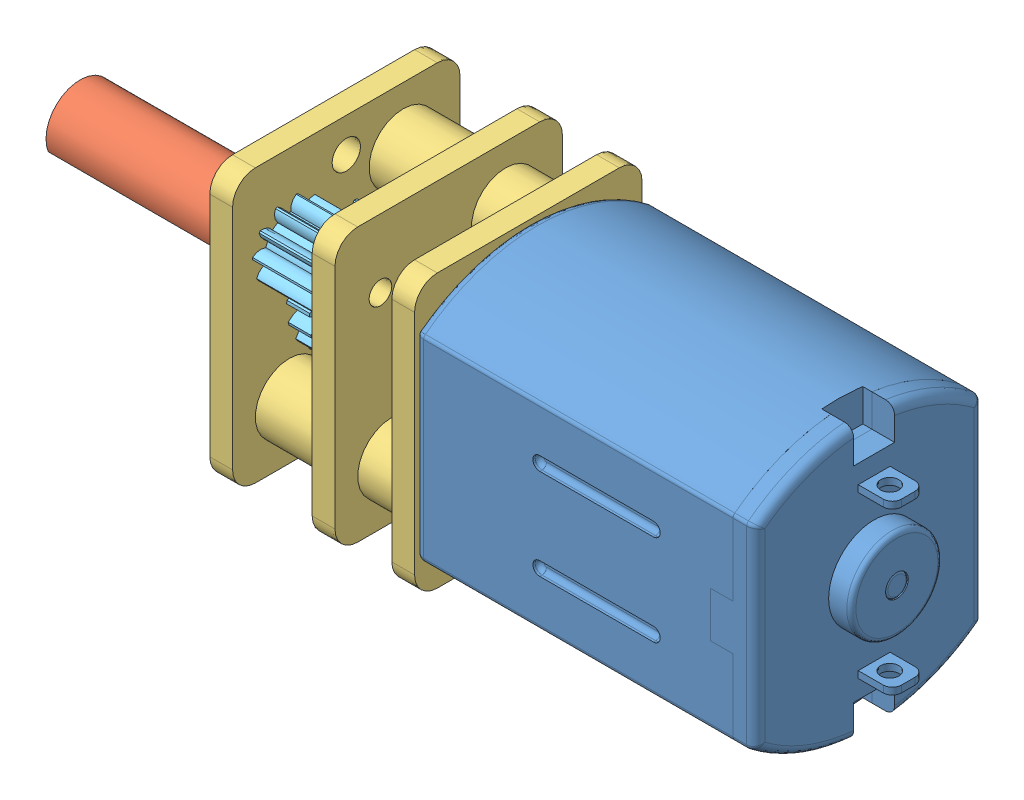
SolidWorks assembly n20 motor, configuration 轴长10mm. Lengths in mm.
Overall size (36.2 12.14 10.87).
11 component instances, 5 part files, 21 mates.
Components (placement in the parent):
- motor-1: motor [默认] at (-3.4114 0.0905 -5.0483)
- n20_shaft-1: n20_shaft [10mm] at (-13.1114 0.0905 -0.0483) x (0 -0.354131 -0.935196) z (0 0.935196 -0.354131) size (3 12 3)
- n20_gearbox-1: n20_gearbox [默认] at (-11.4114 0.0905 -0.0483) x (0 1 0) z (-1 0 0)
- cross recessed countersunk head screws gb1-1: cross recessed countersunk head screws gb1 [GB_CROSS_SCREWS_TYPE4 M1.6X3-2  H type-N] at (-12.4614 -3.4095 2.4517)
- cross recessed countersunk head screws gb1-2: cross recessed countersunk head screws gb1 [GB_CROSS_SCREWS_TYPE4 M1.6X3-2  H type-N] at (-12.4614 3.5905 -2.5483) x (1 0 0) z (0 0.116872 0.993147)
- spur gear_gb-1: spur gear_gb [GB - Spur gear 0.25M 10T 20PA 2FW ---S10A75H50L1.0N] at (-8.4114 -2.9095 -2.5483) x (1 0 0) z (0 -0.845955 0.533254)
- spur gear_gb-2: spur gear_gb [GB - Spur gear 0.25M 10T 20PA 2FW ---S10A75H50L1.0N] at (-4.4114 0.0905 -0.0483) x (-1 0 0) z (0 0.404067 -0.914729)
- spur gear_gb-4: spur gear_gb [GB - Spur gear 0.25M 16T 20PA 2FW ---S16A75H50L1.0N] at (-6.4114 -2.9095 -2.5483) x (1 0 0) z (0 -0.712706 0.701463)
- spur gear_gb-6: spur gear_gb [GB - Spur gear 0.25M 19T 20PA 2FW ---S19A75H50L1.0N] at (-9.9114 0.0905 -0.0483) x (1 0 0) z (0 0.321468 -0.94692)
- spur gear_gb-8: spur gear_gb [GB - Spur gear 0.25M 11T 20PA 3FW ---S11A75H50L1.0N] at (-10.9114 3.0905 2.9517) x (1 0 0) z (0 -0.604063 0.796937)
- spur gear_gb-10: spur gear_gb [GB - Spur gear 0.25M 19T 20PA 1FW ---S19A75H50L1.0N] at (-11.4114 0.0905 -0.0483) x (1 0 0) z (0 -0.330889 0.94367)
Mates (geometry in assembly coordinates):
- 同心1: concentric: cylinder of motor-1 through (-6.4114 0.0905 -0.0483) axis (1 0 0) radius 1; cylinder of n20_gearbox-1 through (-3.4114 0.0905 -0.0483) axis (-1 0 0) radius 0.5329
- 重合1: coincident: plane of motor-1 through (-3.4114 -5.9095 4.9517) normal (-1 0 0); plane of n20_gearbox-1 through (-3.4114 0.0905 -0.0483) normal (1 0 0)
- 重合2: coincident: plane of motor-1 through (-3.4114 0.0905 4.9517) normal (0 0 1); plane of n20_gearbox-1 through (-3.4114 6.0905 4.9517) normal (0 0 1)
- 同心2: concentric: cylinder of n20_shaft-1 through (-23.1114 0.0905 -0.0483) axis (1 0 0) radius 1.5; cylinder of n20_gearbox-1 through (-12.4114 0.0905 -0.0483) axis (1 0 0) radius 1.5
- 同心3: concentric: cylinder of n20_gearbox-1 through (-7.9114 3.5905 -2.5483) axis (-1 0 0) radius 0.9; cone of cross recessed countersunk head screws gb1-2 through (-11.4614 3.5905 -2.5483) axis (1 0 0)
- 重合4: coincident: cone of n20_gearbox-1 through (-12.4114 3.5905 -2.5483) axis (1 0 0); cone of cross recessed countersunk head screws gb1-2 through (-11.4614 3.5905 -2.5483) axis (1 0 0)
- 同心8: concentric: cylinder of n20_gearbox-1 through (-7.9114 -3.4095 2.4517) axis (-1 0 0) radius 0.9; cylinder of cross recessed countersunk head screws gb1-1 through (-7.9456 -3.4095 2.4517) axis (1 0 0) radius 0.8
- 重合5: coincident: cone of n20_gearbox-1 through (-12.4114 -3.4095 2.4517) axis (1 0 0); cone of cross recessed countersunk head screws gb1-1 through (-11.4614 -3.4095 2.4517) axis (1 0 0)
- 同心10: concentric: cylinder of motor-1 through (-6.4114 0.0905 -0.0483) axis (1 0 0) radius 1; cylinder of spur gear_gb-2 through (-54.4115 0.0905 -0.0483) axis (1 0 0) radius 0.5
- 同心11: concentric: cylinder of n20_gearbox-1 through (-3.4114 -2.9095 -2.5483) axis (-1 0 0) radius 0.5; cylinder of spur gear_gb-4 through (43.5886 -2.9095 -2.5483) axis (-1 0 0) radius 0.5
- 重合6: coincident: plane of n20_gearbox-1 through (-4.4114 0.0905 -0.0483) normal (-1 0 0); plane of spur gear_gb-4 through (-4.4114 -2.9095 -2.5483) normal (1 0 0)
- 同心12: concentric: cylinder of n20_gearbox-1 through (-6.9114 0.0905 -0.0483) axis (-1 0 0) radius 0.5; cylinder of spur gear_gb-6 through (40.0886 0.0905 -0.0483) axis (-1 0 0) radius 0.5
- 重合7: coincident: plane of n20_gearbox-1 through (-7.9114 0.0905 -0.0483) normal (-1 0 0); plane of spur gear_gb-6 through (-7.9114 0.0905 -0.0483) normal (1 0 0)
- 同心13: concentric: cylinder of spur gear_gb-1 through (41.5886 -2.9095 -2.5483) axis (-1 0 0) radius 0.5; cylinder of spur gear_gb-4 through (43.5886 -2.9095 -2.5483) axis (-1 0 0) radius 0.5
- 重合8: coincident: plane of spur gear_gb-1 through (-6.4114 -2.9095 -2.5483) normal (1 0 0); plane of spur gear_gb-4 through (-6.4114 -2.9095 -2.5483) normal (-1 0 0)
- 同心14: concentric: cylinder of n20_gearbox-1 through (-6.9114 3.0905 2.9517) axis (-1 0 0) radius 0.5; cylinder of spur gear_gb-8 through (39.0886 3.0905 2.9517) axis (-1 0 0) radius 0.5
- 同心15: concentric: cylinder of spur gear_gb-6 through (40.0886 0.0905 -0.0483) axis (-1 0 0) radius 0.5; cylinder of spur gear_gb-10 through (38.5886 0.0905 -0.0483) axis (-1 0 0) radius 0.5
- 重合9: coincident: plane of n20_gearbox-1 through (-7.9114 0.0905 -0.0483) normal (-1 0 0); plane of spur gear_gb-8 through (-7.9114 3.0905 2.9517) normal (1 0 0)
- 重合10: coincident: plane of n20_gearbox-1 through (-11.4114 0.0905 -0.0483) normal (1 0 0); plane of spur gear_gb-10 through (-11.4114 0.0905 -0.0483) normal (-1 0 0)
- 重合11: coincident: plane of n20_gearbox-1 through (-4.4114 0.0905 -0.0483) normal (-1 0 0); plane of spur gear_gb-2 through (-4.4114 0.0905 -0.0483) normal (1 0 0)
- Coincident2: coincident: plane of n20_shaft-1 through (-13.1114 0.0905 -0.0483) normal (-1 0 0); plane of n20_gearbox-1 through (-13.1114 0.0905 -0.0483) normal (-1 0 0)
